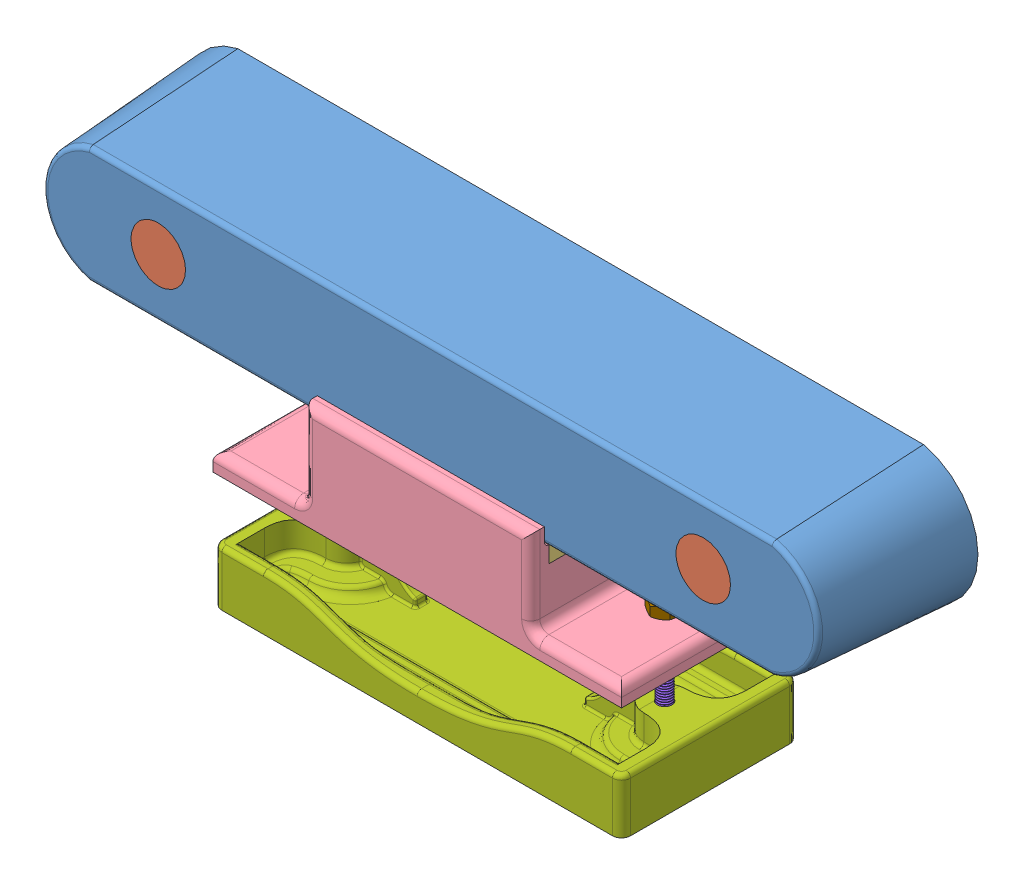
SolidWorks assembly Zed+Stand, configuration Default. Lengths in mm.
Overall size (175 72.87 42.17).
16 component instances, 10 part files, 22 mates.
Components (placement in the parent):
- ZED-camera-1: ZED-camera [Default] at origin size (175 30 38)
  - ZED-Body-1: ZED-Body [Default] at origin size (175 30 38)
  - ZED-Glass-1: ZED-Glass [Default] at (-60 0 31) size (12 12 2)
  - ZED-Glass-2: ZED-Glass [Default] at (60 0 31) size (12 12 2)
- stand_lite-1: stand_lite [Default] x (0 0 -1) z (1 0 0)
- stand_zed_up-1: stand_zed_up [Default] x (0 0 -1) z (1 0 0) size (35 10.88 50)
- stand_zed_base-1: stand_zed_base [Default] x (0 0 -1) z (1 0 0) size (39 23.06 90)
- stand_gum-1: stand_gum [Default] at (0.0001 -14.465 15.5988) x (-1 0 0) z (0 0.997801 -0.066274) size (47 28.27 0.5)
- screw-1: screw [Default] at (0.0001 -20.6462 16.0094) x (0.999737 0.00152 0.022883) z (-0.022933 0.066256 0.997539) size (15 15 15)
- standdown-1: standdown [Default] at (0 -45.8745 16.5) x (1 0 0) z (0 -1 0) size (90 41.34 14.17)
- slotted cheese head screw_iso-1: slotted cheese head screw_iso [ISO 1207 - M3 x 30 - 30S] at (35 -55.8745 16.5) x (0 1 0) z (0.546944 0 -0.837169) size (32.01 5.5 5.5)
- slotted cheese head screw_iso-3: slotted cheese head screw_iso [ISO 1207 - M3 x 30 - 30S] at (-35 -55.8745 16.5) x (0 1 0) z (0.546944 0 0.837169) size (32.01 5.5 5.5)
- M3 Nut2-6: M3 Nut2 [Default] at (-35 -27.3011 16.5) x (1 0 0) z (0 1 0) size (5.5 6.35 2.74)
- M3 Nut2-7: M3 Nut2 [Default] at (-35 -33.7011 16.5) x (1 0 0) z (0 1 0) size (5.5 6.35 2.74)
- M3 Nut2-8: M3 Nut2 [Default] at (35 -33.7011 16.5) x (-1 0 0) z (0 1 0) size (5.5 6.35 2.74)
- M3 Nut2-9: M3 Nut2 [Default] at (35 -27.3011 16.5) x (-1 0 0) z (0 1 0) size (5.5 6.35 2.74)
Mates (geometry in assembly coordinates):
- SulPosto1: in place: plane of ? through (0 0 0) normal (1 0 0); moOrthogonalPlaneRef_w of ? through (-55 0 0) axis (0 0 1); plane of ? through (0 0 0) normal (0 0 -1); unknown of ?
- Coincidente1: coincident aligned: 
- Coincidente2: coincident aligned: plane of stand_lite-1 through (0 0 0) normal (0 1 0)
- Coincidente3: coincident anti-aligned: plane of stand_lite-1 through (0 0 0) normal (0 0 -1)
- Coincidente23: coincident: point of stand_lite-1; point of stand_zed_base-1
- Concentrico4: concentric anti-aligned: circle of stand_zed_up-1; cylinder of stand_gum-1 through (0.0001 -14.9639 15.632) axis (0 0.997801 -0.066274) radius 3
- Coincidente29: coincident anti-aligned: plane of stand_zed_up-1 through (25 -13.3092 33) normal (0 0.997801 -0.066274); plane of stand_gum-1 through (0.0001 -14.465 15.5988) normal (0 -0.997801 0.066274)
- Coincidente31: coincident anti-aligned: plane of stand_gum-1 through (0.0001 -14.465 15.5988) normal (-1 0 0); plane of assembly through (0 0 0) normal (1 0 0)
- Coincidente32: coincident anti-aligned: plane of stand_zed_up-1 through (-25.01 -19.5011 32) normal (0 -1 0); plane of stand_zed_base-1 through (-25.01 -19.5011 32) normal (0 1 0)
- Coincidente33: coincident aligned: plane of stand_zed_up-1 through (25 -10.6168 -3) normal (0 0 -1); plane of stand_zed_base-1 through (25 -10.6168 -3) normal (0 0 -1)
- Concentrico5: concentric aligned: cylinder of ZED-camera-1/ZED-Body-1 through (0.0001 -3.9881 14.903) axis (0 -0.997801 0.066274) radius 2.65; cylinder of screw-1 through (0.0001 -24.2166 16.2465) axis (0 -0.997801 0.066274) radius 2
- Coincidente34: coincident anti-aligned: plane of stand_zed_up-1 through (3.264 -15.9565 15.6979) normal (0 -0.997801 0.066274); plane of screw-1 through (1.4093 -15.9544 15.7302) normal (0 0.997801 -0.066274)
- Parallel1: parallel aligned: plane of stand_zed_base-1 through (0 -32.5011 0) normal (0 -1 0); plane of standdown-1 through (0 -57.8745 16.5) normal (0 -1 0)
- Coincident7: coincident aligned: line of standdown-1 through (35 -45.8745 16.5) axis (0 -1 0); line of slotted cheese head screw_iso-1 through (35 -52.1781 16.5) axis (0 -1 0)
- Coincident8: coincident anti-aligned: plane of standdown-1 through (35 -53.8745 16.5) normal (0 -1 0); plane of slotted cheese head screw_iso-1 through (36.2558 -53.8745 17.3204) normal (0 1 0)
- Distance1: distance = 13.3734 mm anti-aligned: plane of standdown-1 through (0 -45.8745 16.5) normal (0 1 0); plane of stand_zed_base-1 through (0 -32.5011 0) normal (0 -1 0)
- Coincident10: coincident aligned: plane of stand_zed_base-1 through (-45 -32.5011 -1) normal (-1 0 0); plane of standdown-1 through (-45 -57.8745 -3) normal (-1 0 0)
- Coincident17: coincident aligned: plane of stand_zed_base-1 through (25 -10.6168 -3) normal (0 0 -1); plane of standdown-1 through (-45 -57.8745 -3) normal (0 0 -1)
- Coincident18: coincident anti-aligned: line of stand_zed_base-1 through (-35 -32.5011 16.5) axis (0 1 0); line of M3 Nut-6 through (-35 -26.3716 16.5) axis (0 -1 0)
- Coincident19: coincident anti-aligned: plane of stand_zed_base-1 through (0 -28.5011 0) normal (0 1 0); plane of M3 Nut-6 through (-35 -28.5011 16.5) normal (0 -1 0)
- Coincident21: coincident anti-aligned: plane of stand_zed_base-1 through (0 -32.5011 0) normal (0 -1 0); plane of M3 Nut-7 through (-35 -32.5011 16.5) normal (0 1 0)
- Coincident22: coincident anti-aligned: line of stand_zed_base-1 through (-35 -32.5011 16.5) axis (0 1 0); line of M3 Nut-7 through (-35 -34.1161 16.5) axis (0 -1 0)
